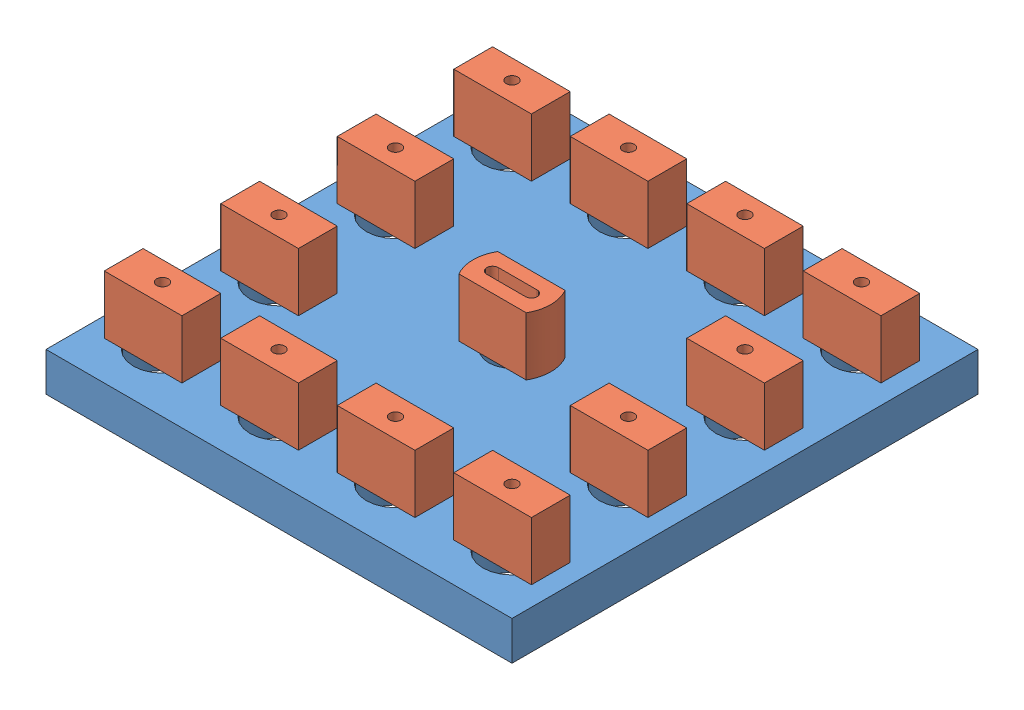
SolidWorks assembly plaque et pièce, configuration Défaut. Lengths in mm.
Overall size (120 25 120).
14 component instances, 2 part files, 6 mates.
Components (placement in the parent):
- plaque de base-1: plaque de base [Défaut] at origin size (120 10 120)
- Copie de pièce^plaque et pièce-1: Copie de pièce^plaque et pièce [Défaut] at (-45 10 -45) size (20 15 10) (virtual)
- Copie de pièce^plaque et pièce-13: Copie de pièce^plaque et pièce [Défaut] at (-45 10 -15) size (20 15 10) (virtual)
- Copie de pièce^plaque et pièce-14: Copie de pièce^plaque et pièce [Défaut] at (-45 10 15) size (20 15 10) (virtual)
- Copie de pièce^plaque et pièce-15: Copie de pièce^plaque et pièce [Défaut] at (-45 10 45) size (20 15 10) (virtual)
- Copie de pièce^plaque et pièce-16: Copie de pièce^plaque et pièce [Défaut] at (-15 10 -45) size (20 15 10) (virtual)
- Copie de pièce^plaque et pièce-17: Copie de pièce^plaque et pièce [Défaut] at (-15 10 45) size (20 15 10) (virtual)
- Copie de pièce^plaque et pièce-18: Copie de pièce^plaque et pièce [Défaut] at (15 10 -45) size (20 15 10) (virtual)
- Copie de pièce^plaque et pièce-19: Copie de pièce^plaque et pièce [Défaut] at (15 10 45) size (20 15 10) (virtual)
- Copie de pièce^plaque et pièce-20: Copie de pièce^plaque et pièce [Défaut] at (45 10 -45) size (20 15 10) (virtual)
- Copie de pièce^plaque et pièce-21: Copie de pièce^plaque et pièce [Défaut] at (45 10 -15) size (20 15 10) (virtual)
- Copie de pièce^plaque et pièce-22: Copie de pièce^plaque et pièce [Défaut] at (45 10 15) size (20 15 10) (virtual)
- Copie de pièce^plaque et pièce-23: Copie de pièce^plaque et pièce [Défaut] at (45 10 45) size (20 15 10) (virtual)
- Copie de pièce^plaque et pièce-24: Copie de pièce^plaque et pièce [oblong] at (0 10 0) size (20 15 10) (virtual)
Mates (geometry in assembly coordinates):
- Parallèle1: parallel aligned: plane of plaque de base-1 through (-60 10 60) normal (0 0 1); plane of pièce-1 through (-55 25 -40) normal (0 0 1)
- Coïncidente3: coincident anti-aligned: plane of plaque de base-1 through (0 10 0) normal (0 1 0); plane of pièce-1 through (-45 10 -45) normal (0 -1 0)
- Coaxiale2: concentric aligned: cylinder of plaque de base-1 through (-45 0 -45) axis (0 1 0) radius 7.5; cylinder of pièce-1 through (-45 10 -45) axis (0 1 0) radius 1.5
- Coïncidente6: coincident anti-aligned: plane of plaque de base-1 through (0 10 0) normal (0 1 0); plane of pièce-15 through (0 10 0) normal (0 -1 0)
- Parallèle4: parallel aligned: plane of plaque de base-1 through (-60 10 60) normal (0 0 1); plane of pièce-15 through (-10 25 5) normal (0 0 1)
- Coaxiale4: concentric aligned: cylinder of plaque de base-1 through (0 0 0) axis (0 1 0) radius 6; point of pièce-15
